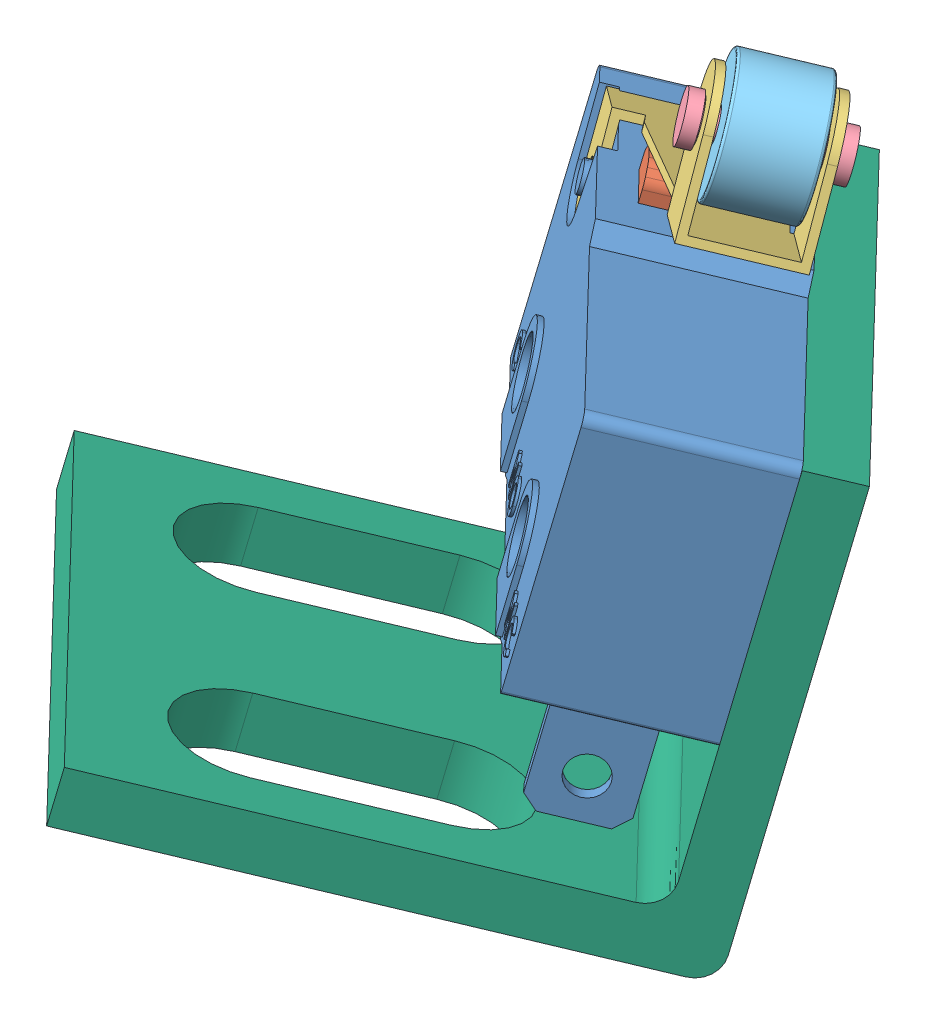
SolidWorks assembly Limit SwitchBottom, configuration Default. Lengths in mm.
Overall size (29.89 30.23 31.62).
6 component instances, 6 part files, 12 mates.
Components (placement in the parent):
- Body-1: Body [Default] at (0.6339 15.052 8.9534) x (0.692905 0.10626 0.713156) z (-0.712684 0.250975 0.655052) size (19.88 14.3 6.9)
- Switch_Button-1: Switch_Button [Default] at (2.7559 13.8668 16.6776) x (0.692905 0.10626 0.713156) z (-0.712684 0.250975 0.655052) size (2 4 4)
- Link-1: Link [Default] at (-0.9544 15.5617 11.9916) x (0.695189 0.377522 0.61171) z (-0.712684 0.250975 0.655052) size (18.04 8.82 6.05)
- Wheel shaft-1: Wheel shaft [Default] at (11.8225 23.9828 18.7734) x (-0.697489 -0.35306 -0.623585) z (-0.712684 0.250975 0.655052) size (1.82 1.82 5.1)
- Wheel-1: Wheel [Default] at (11.0706 24.2476 19.4644) x (0.037878 0.946213 -0.32132) z (-0.712684 0.250975 0.655052) size (4.67 4.67 2.99)
- GaCTHanhTrinh-1: GaCTHanhTrinh [Default] at (-8.5333 1.8311 19.8302) x (-0.109379 -0.962144 0.249631) z (-0.712684 0.250975 0.655052) size (17 19.88 20)
Mates (geometry in assembly coordinates):
- Coincident1: coincident anti-aligned: plane of Body-1 through (0.7291 15.0673 17.0658) normal (0.712684 -0.250975 -0.655052); plane of Switch_Button-1 through (1.0751 18.111 16.2761) normal (-0.712684 0.250975 0.655052)
- Coincident2: coincident anti-aligned: plane of Body-1 through (4.9656 14.2759 15.8719) normal (-0.692905 -0.10626 -0.713156); plane of Switch_Button-1 through (5.3116 17.3196 15.0822) normal (0.692905 0.10626 0.713156)
- Concentric1: concentric aligned: cylinder of Body-1 through (-1.5949 14.8411 15.6163) axis (-0.712684 0.250975 0.655052) radius 0.55; cylinder of Link-1 through (5.9774 12.1745 8.6564) axis (-0.712684 0.250975 0.655052) radius 0.65
- Tangent1: tangent anti-aligned: cylinder of Switch_Button-1 through (2.9357 17.2031 15.5951) axis (-0.712684 0.250975 0.655052) radius 0.5; plane of Link-1 through (-0.9544 15.5617 11.9916) normal (0.093772 -0.891341 0.443529)
- Symmetric1: symmetric aligned: plane of Body-1 through (14.0179 16.1214 23.1053) normal (0.712684 -0.250975 -0.655052); plane of Link-1 through (9.3855 17.7527 27.3631) normal (-0.712684 0.250975 0.655052); plane of Body-1 through (-0.9544 15.5617 11.9916) normal (-0.712684 0.250975 0.655052)
- Concentric2: concentric aligned: cylinder of Link-1 through (7.9954 25.3305 22.291) axis (0.712684 -0.250975 -0.655052) radius 0.75; cylinder of Wheel shaft-1 through (8.1878 25.2628 22.1141) axis (0.712684 -0.250975 -0.655052) radius 0.5
- Symmetric2: symmetric aligned: plane of Link-1 through (-0.9544 15.5617 11.9916) normal (-0.712684 0.250975 0.655052); plane of Wheel shaft-1 through (8.1878 25.2628 22.1141) normal (-0.712684 0.250975 0.655052); plane of Wheel shaft-1 through (11.8225 23.9828 18.7734) normal (0.712684 -0.250975 -0.655052)
- Concentric3: concentric aligned: cylinder of Wheel shaft-1 through (8.1878 25.2628 22.1141) axis (0.712684 -0.250975 -0.655052) radius 0.5; cylinder of Wheel-1 through (8.9397 24.998 21.423) axis (0.712684 -0.250975 -0.655052) radius 0.6
- Symmetric3: symmetric aligned: plane of Link-1 through (-0.9544 15.5617 11.9916) normal (-0.712684 0.250975 0.655052); plane of Wheel-1 through (8.9397 24.998 21.423) normal (-0.712684 0.250975 0.655052); plane of Wheel-1 through (11.0706 24.2476 19.4644) normal (0.712684 -0.250975 -0.655052)
- Concentric4: concentric aligned: cylinder of Body-1 through (12.5252 8.2881 19.1394) axis (-0.712684 0.250975 0.655052) radius 1.225; cylinder of GaCTHanhTrinh-1 through (11.4562 8.6645 20.122) axis (-0.712684 0.250975 0.655052) radius 1.225
- Concentric5: concentric aligned: cylinder of Body-1 through (5.8109 7.2584 12.2289) axis (-0.712684 0.250975 0.655052) radius 1.225; cylinder of GaCTHanhTrinh-1 through (4.7419 7.6349 13.2115) axis (-0.712684 0.250975 0.655052) radius 1.225
- Coincident3: coincident anti-aligned: plane of Body-1 through (14.0179 16.1214 23.1053) normal (0.712684 -0.250975 -0.655052); plane of GaCTHanhTrinh-1 through (12.6108 1.3484 27.2345) normal (-0.712684 0.250975 0.655052)
